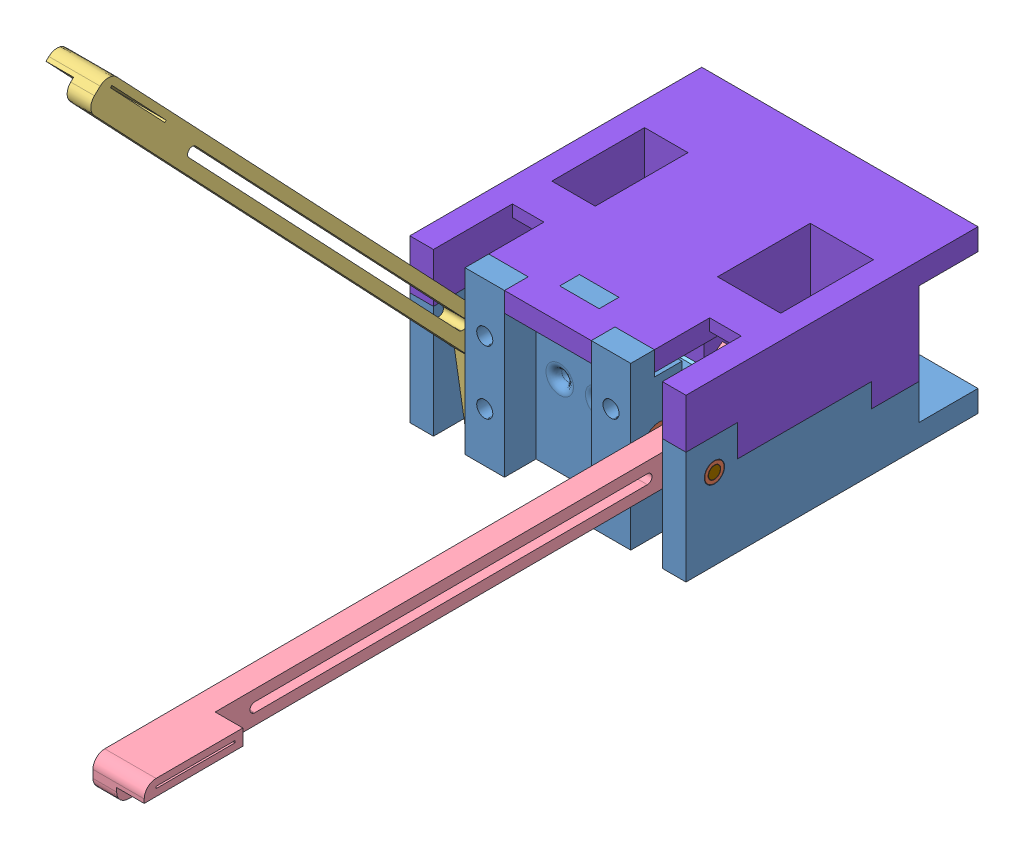
SolidWorks assembly mid_assembly, configuration Default. Lengths in mm.
Overall size (70 144 211.34).
16 component instances, 9 part files, 37 mates.
Components (placement in the parent):
- mid_body_bottom-1: mid_body_bottom [Default] at (-55.401 28.8431 94.1626) size (70 41 74)
- bushing_other-3: bushing_other [Default] at (-26.301 28.8431 116.4543) x (0 0.920948 0.389685) z (0 0.389685 -0.920948) size (7.9 5.9 7.9)
- bushing_other-4: bushing_other [Default] at (-84.501 28.8431 116.4543) x (0 -0.148892 -0.988853) z (0 0.988853 -0.148892) size (7.9 5.9 7.9)
- bushing_other-6: bushing_other [Default] at (-34.501 28.8431 116.4543) x (0 -0.148892 -0.988853) z (0 0.988853 -0.148892) size (7.9 5.9 7.9)
- bushing_other-7: bushing_other [Default] at (-76.301 28.8431 116.4543) x (0 0.583494 0.812117) z (0 0.812117 -0.583494) size (7.9 5.9 7.9)
- geared_bar_left-1: geared_bar_left [Default] at (-83.401 28.8431 116.4543) x (0 -0.687852 0.725851) z (0 0.725851 0.687852) size (34.71 13 165.5)
- geared_bar_right-2: geared_bar_right [Default] at (-27.401 28.8431 116.4543) x (0 0.999995 0.00307) z (0 -0.00307 0.999995) size (34.71 13 165.5)
- tg9e_micro_servo-1: tg9e_micro_servo [Default] at (-64.351 20.3431 81.6626) x (0 0 1) z (0 1 0) size (34 30 12)
- servo_gear-1: servo_gear [Default] at (-28.351 20.3431 87.1626) x (0 0.698733 -0.715382) z (0 0.715382 0.698733) size (22 6 22)
- tg9e_servo_horn_x_trimmed-1: tg9e_servo_horn_x_trimmed [Default] at (-36.851 20.3431 87.1626) x (0 0.677981 -0.735079) z (0 -0.735079 -0.677981) size (24 4.1 17.3)
- mid_body_top-1: mid_body_top [Default] at (-55.401 28.8431 94.1626) size (70 26.5 74)
- tg9e_micro_servo-2: tg9e_micro_servo [Default] at (-46.351 37.3431 81.6626) x (0 0 1) z (0 -1 0) size (34 30 12) (hidden)
- servo_gear-2: servo_gear [Default] at (-82.351 37.3431 87.1626) x (0 -0.361795 0.932258) z (0 0.932258 0.361795) size (22 6 22) (hidden)
- tg9e_servo_horn_x_trimmed-2: tg9e_servo_horn_x_trimmed [Default] at (-73.851 37.3431 87.1626) x (0 -0.388318 0.921526) z (0 -0.921526 -0.388318) size (24 4.1 17.3) (hidden)
- solid_rod_3_20mm-1: solid_rod_3_20mm [Default] at (-20.401 28.8431 116.4543) x (0 -0.381849 0.924225) z (0 -0.924225 -0.381849) size (3 20 3)
- solid_rod_3_20mm-2: solid_rod_3_20mm [Default] at (-70.401 28.8431 116.4543) x (0 -0.381849 0.924225) z (0 -0.924225 -0.381849) size (3 20 3)
Mates (geometry in assembly coordinates):
- Concentric4: concentric anti-aligned: cylinder of mid_body_bottom-1 through (-90.402 28.8431 116.4543) axis (1 0 0) radius 2.575; cylinder of bushing_other-3 through (-20.401 28.8431 116.4543) axis (-1 0 0) radius 2.45
- Coincident4: coincident anti-aligned: plane of mid_body_bottom-1 through (-24.401 28.8431 116.4543) normal (-1 0 0); plane of bushing_other-3 through (-24.401 28.8431 116.4543) normal (1 0 0)
- Concentric5: concentric anti-aligned: cylinder of mid_body_bottom-1 through (-20.4 28.8431 116.4543) axis (-1 0 0) radius 2.575; cylinder of bushing_other-4 through (-90.401 28.8431 116.4543) axis (1 0 0) radius 2.45
- Coincident5: coincident anti-aligned: plane of mid_body_bottom-1 through (-86.401 28.8431 116.4543) normal (1 0 0); plane of bushing_other-4 through (-86.401 28.8431 116.4543) normal (-1 0 0)
- Concentric6: concentric aligned: cylinder of mid_body_bottom-1 through (-40.401 28.8431 116.4543) axis (1 0 0) radius 2.575; cylinder of bushing_other-6 through (-40.401 28.8431 116.4543) axis (1 0 0) radius 2.45
- Coincident6: coincident anti-aligned: plane of mid_body_bottom-1 through (-36.401 28.8431 116.4543) normal (1 0 0); plane of bushing_other-6 through (-36.401 28.8431 116.4543) normal (-1 0 0)
- Concentric7: concentric aligned: cylinder of mid_body_bottom-1 through (-70.401 28.8431 116.4543) axis (-1 0 0) radius 2.575; cylinder of bushing_other-7 through (-70.401 28.8431 116.4543) axis (-1 0 0) radius 2.45
- Coincident7: coincident anti-aligned: plane of mid_body_bottom-1 through (-74.401 28.8431 116.4543) normal (-1 0 0); plane of bushing_other-7 through (-74.401 28.8431 116.4543) normal (1 0 0)
- Distance1: distance = 1 mm anti-aligned: plane of geared_bar_right-2 through (-27.401 28.8431 116.4543) normal (1 0 0); plane of mid_body_bottom-1 through (-26.401 8.3431 70.1626) normal (-1 0 0)
- Distance2: distance = 1 mm anti-aligned: plane of geared_bar_left-1 through (-83.401 28.8431 116.4543) normal (-1 0 0); plane of mid_body_bottom-1 through (-84.401 8.3431 70.1626) normal (1 0 0)
- Coincident8: coincident anti-aligned: plane of mid_body_bottom-1 through (-55.401 14.3431 94.1626) normal (0 1 0); plane of tg9e_micro_servo-1 through (-41.351 14.3431 70.1626) normal (0 -1 0)
- Coincident13: coincident anti-aligned: plane of mid_body_bottom-1 through (-41.401 79.4527 93.1626) normal (0 0 -1); plane of tg9e_micro_servo-1 through (-41.351 26.3431 93.1626) normal (0 0 1)
- Concentric16: concentric aligned: cylinder of tg9e_micro_servo-1 through (-34.351 20.3431 87.1626) axis (-1 0 0) radius 2.5; cylinder of tg9e_servo_horn_x_trimmed-1 through (-34.351 20.3431 87.1626) axis (-1 0 0) radius 2.5
- Coincident17: coincident anti-aligned: plane of tg9e_micro_servo-1 through (-34.351 20.3431 87.1626) normal (1 0 0); plane of tg9e_servo_horn_x_trimmed-1 through (-34.351 25.3049 91.739) normal (-1 0 0)
- Concentric17: concentric anti-aligned: cylinder of servo_gear-1 through (-40.1049 20.3431 87.1626) axis (1 0 0) radius 2.6; cylinder of tg9e_servo_horn_x_trimmed-1 through (-32.751 20.3431 87.1626) axis (-1 0 0) radius 1.25
- Parallel2: parallel anti-aligned: plane of servo_gear-1 through (-32.751 23.3191 89.4999) normal (0 -0.78645 -0.617654); plane of tg9e_servo_horn_x_trimmed-1 through (-32.751 32.418 76.8733) normal (0 0.78645 0.617654)
- Coincident18: coincident anti-aligned: plane of servo_gear-1 through (-32.751 20.3431 87.1626) normal (-1 0 0); plane of tg9e_servo_horn_x_trimmed-1 through (-32.751 25.3049 91.739) normal (1 0 0)
- Coincident19: coincident anti-aligned: plane of mid_body_bottom-1 through (-45.851 -1.1811 97.1626) normal (-1 0 0); plane of tg9e_micro_servo-1 through (-45.851 14.3431 98.6626) normal (1 0 0)
- Coincident20: coincident aligned: plane of mid_body_bottom-1 through (-20.401 8.3431 64.6626) normal (1 0 0); plane of mid_body_top-1 through (-20.401 49.3431 64.6626) normal (1 0 0)
- Coincident21: coincident aligned: plane of mid_body_bottom-1 through (-90.401 8.3431 64.6626) normal (0 0 -1); plane of mid_body_top-1 through (-90.401 49.3431 64.6626) normal (0 0 -1)
- Parallel3: parallel aligned: line of servo_gear-2 through (-76.351 36.2207 97.5541) axis (0 0.460059 -0.887888); line of tg9e_servo_horn_x_trimmed-2 through (-76.351 34.7087 99.0744) axis (0 0.460059 -0.887888)
- Concentric18: concentric anti-aligned: cylinder of servo_gear-2 through (-76.351 37.3431 87.1626) axis (-1 0 0) radius 1.5; cylinder of tg9e_servo_horn_x_trimmed-2 through (-77.951 37.3431 87.1626) axis (1 0 0) radius 1.25
- Coincident23: coincident anti-aligned: plane of servo_gear-2 through (-77.951 37.3431 87.1626) normal (1 0 0); plane of tg9e_servo_horn_x_trimmed-2 through (-77.951 43.5634 89.7838) normal (-1 0 0)
- Coincident24: coincident anti-aligned: plane of tg9e_micro_servo-2 through (-76.351 37.3431 87.1626) normal (-1 0 0); plane of tg9e_servo_horn_x_trimmed-2 through (-76.351 43.5634 89.7838) normal (1 0 0)
- Concentric19: concentric aligned: cylinder of tg9e_micro_servo-2 through (-76.351 37.3431 87.1626) axis (1 0 0) radius 1; cylinder of tg9e_servo_horn_x_trimmed-2 through (-76.351 37.3431 87.1626) axis (1 0 0) radius 2.5
- Coincident25: coincident anti-aligned: plane of mid_body_top-1 through (-55.401 43.3431 94.1626) normal (0 -1 0); plane of tg9e_micro_servo-2 through (-69.351 43.3431 70.1626) normal (0 1 0)
- Coincident26: coincident anti-aligned: plane of mid_body_top-1 through (-62.351 58.8673 93.1626) normal (-1 0 0); plane of tg9e_micro_servo-2 through (-62.351 43.3431 98.6626) normal (1 0 0)
- Coincident27: coincident anti-aligned: plane of mid_body_top-1 through (-55.401 -21.7665 93.1626) normal (0 0 -1); plane of tg9e_micro_servo-2 through (-69.351 31.3431 93.1626) normal (0 0 1)
- Coincident29: coincident aligned: plane of bushing_other-6 through (-40.401 28.8431 116.4543) normal (-1 0 0); plane of solid_rod_3_20mm-1 through (-40.401 28.8431 116.4543) normal (-1 0 0)
- Concentric21: concentric aligned: cylinder of bushing_other-6 through (-36.401 28.8431 116.4543) axis (1 0 0) radius 1.6; cylinder of solid_rod_3_20mm-1 through (-40.401 28.8431 116.4543) axis (1 0 0) radius 1.5
- Concentric22: concentric aligned: cylinder of geared_bar_right-2 through (-33.401 28.8431 116.4543) axis (1 0 0) radius 1.5; cylinder of solid_rod_3_20mm-1 through (-40.401 28.8431 116.4543) axis (1 0 0) radius 1.5
- Coincident30: coincident aligned: plane of bushing_other-7 through (-70.401 28.8431 116.4543) normal (1 0 0); plane of solid_rod_3_20mm-2 through (-70.401 28.8431 116.4543) normal (1 0 0)
- Concentric23: concentric aligned: cylinder of bushing_other-4 through (-86.401 28.8431 116.4543) axis (1 0 0) radius 1.6; cylinder of solid_rod_3_20mm-2 through (-90.401 28.8431 116.4543) axis (1 0 0) radius 1.5
- Concentric24: concentric anti-aligned: cylinder of geared_bar_left-1 through (-77.401 28.8431 116.4543) axis (-1 0 0) radius 1.5; cylinder of solid_rod_3_20mm-2 through (-90.401 28.8431 116.4543) axis (1 0 0) radius 1.5
- GearMate1: gear = 22 : 42 mm: cylinder of geared_bar_right-2 through (-33.401 28.8431 116.4543) axis (1 0 0) radius 21; cylinder of servo_gear-1 through (-34.351 20.3431 87.1626) axis (1 0 0) radius 11
- GearMate2: gear = 42 : 22 mm: cylinder of servo_gear-2 through (-76.351 37.3431 87.1626) axis (-1 0 0) radius 11; cylinder of geared_bar_left-1 through (-77.401 28.8431 116.4543) axis (-1 0 0) radius 21
- Coincident31: coincident anti-aligned: plane of mid_body_bottom-1 through (-55.401 28.8431 94.1626) normal (0 1 0); plane of mid_body_top-1 through (-55.401 28.8431 94.1626) normal (0 -1 0)
